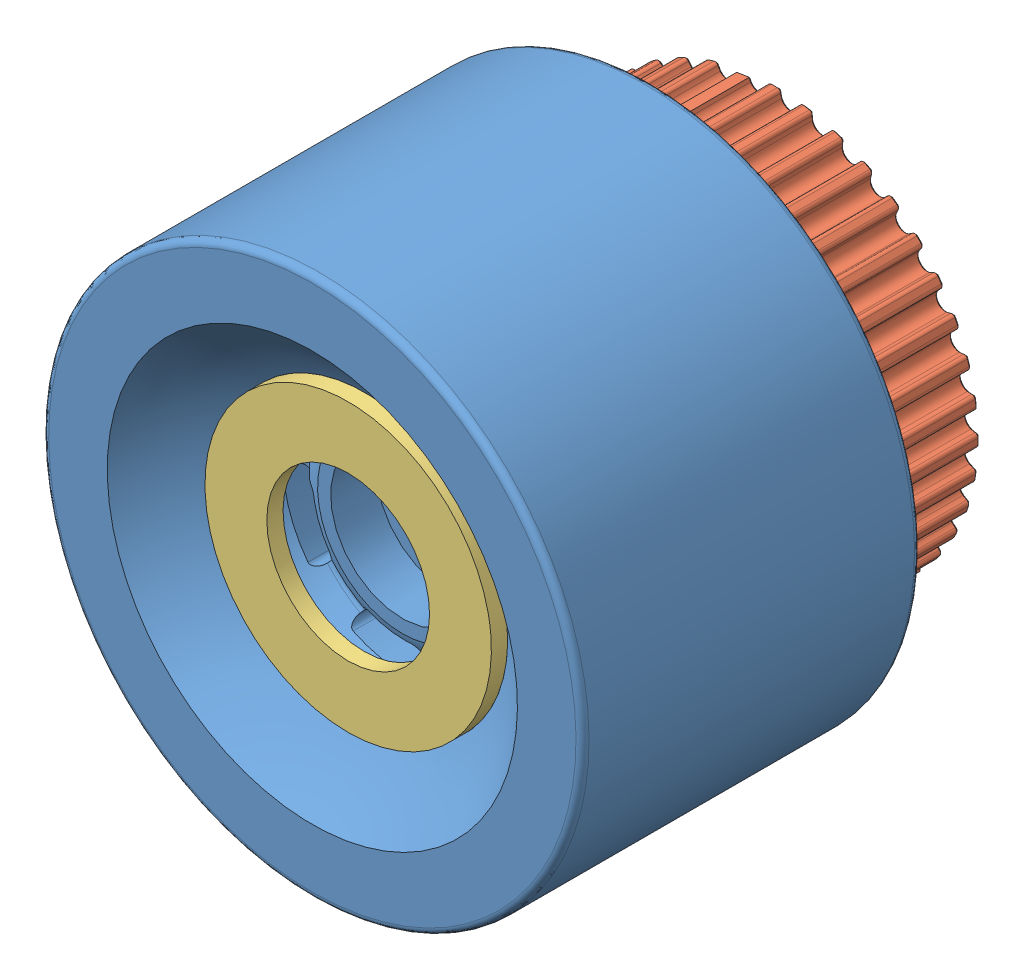
SolidWorks assembly Assem wheel hub pulley, configuration Default. Lengths in mm.
Overall size (116.81 116.81 148.77).
3 component instances, 3 part files, 6 mates.
Components (placement in the parent):
- 83mm wheel-1: 83mm wheel [Default] x (0.633809 0.77349 0) z (0 0 1) size (83 83 52)
- 40T 5MGT-1: 40T 5MGT [Default] at (0 0 -26) x (-0.97385 -0.227194 0) z (0.227194 -0.97385 0) size (62.8 19.08 62.8)
- M24 washer-1: M24 washer [Default] at (0 0 20.5) x (0.151922 -0.988392 0) z (0.988392 0.151922 0) size (44 2.5 44)
Mates (geometry in assembly coordinates):
- Coincident4: coincident: point of 83mm wheel-1; point of assembly
- Coincident7: coincident anti-aligned: plane of 83mm wheel-1 through (0 0 -26) normal (0 0 -1); plane of 40T 5MGT-1 through (0 0 -26) normal (0 0 1)
- Concentric2: concentric aligned: cylinder of 83mm wheel-1 through (0 0 26) axis (0 0 -1) radius 41.5; circle of 40T 5MGT-1
- Coincident9: coincident anti-aligned: axis of 83mm wheel-1 through (0 0 -5.2) axis (0 0 1); line of assembly
- Parallel1: parallel anti-aligned: plane of 83mm wheel-1 through (-10.0554 8.2395 12.2) normal (0 0 1); plane of M24 washer-1 through (0 0 18) normal (0 0 -1)
- Coincident10: coincident aligned: circle of 83mm wheel-1; circle of M24 washer-1
